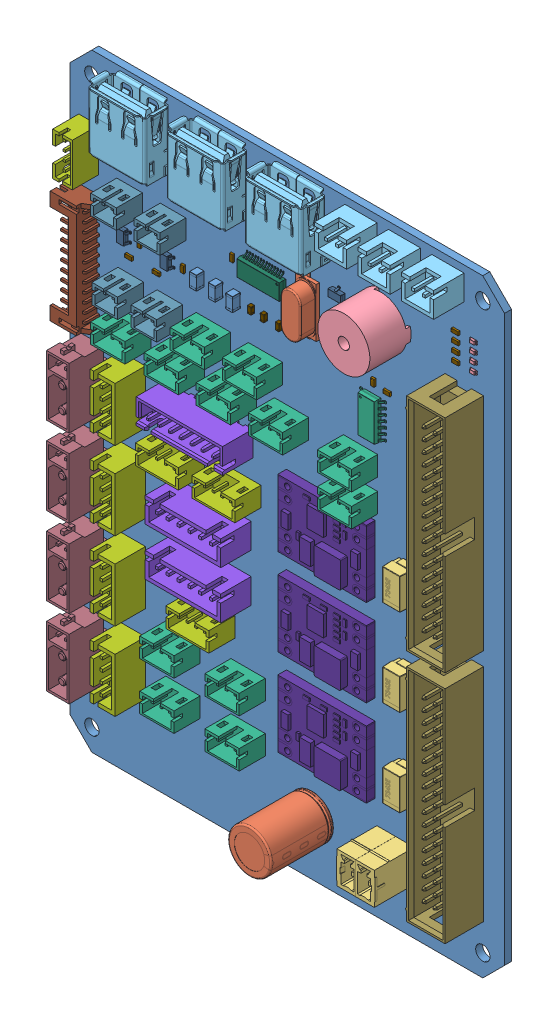
SolidWorks assembly Main Board, configuration 預設. Lengths in mm.
Overall size (100 140 20.2).
81 component instances, 26 part files, 0 mates.
Components (placement in the parent):
- BoardOutline_Main Board-1: BoardOutline_Main Board [預設] at origin size (100 140 1.6)
- XTAL_ECS-120-32-5P-TR_ECS-120-32-5P-TR_1-1: XTAL_ECS-120-32-5P-TR_ECS-120-32-5P-TR_1 [預設] at (267.025 238.5 1.6) x (0 1 0) z (0 0 1) size (13.2 4.8 4.31)
- FCI_06-381-2PIN_(180)_2_Pin_1-1: FCI_06-381-2PIN_(180)_2_Pin_1 [預設] at (287.025 139.5 1.6) size (8.81 7.6 12.7)
- LED_0603_1608_BLUE_LED_1-1: LED_0603_1608_BLUE_LED_1 [預設] at (305 250.5 1.6) size (1.6 0.8 0.53)
- LED_0603_1608_BLUE_LED_1-2: LED_0603_1608_BLUE_LED_1 [預設] at (305.025 248.5 1.6) size (1.6 0.8 0.53)
- LED_0603_1608_BLUE_LED_1-3: LED_0603_1608_BLUE_LED_1 [預設] at (305.025 246.5 1.6) size (1.6 0.8 0.53)
- LED_0603_1608_BLUE_LED_1-4: LED_0603_1608_BLUE_LED_1 [預設] at (305.025 244.5 1.6) size (1.6 0.8 0.53)
- OST_USB-A1HSW6_USB-A1HSW6_1-1: OST_USB-A1HSW6_USB-A1HSW6_1 [預設] at (229 256.5 1.6) x (-1 0 0) z (0 0 1) size (15.8 14.1 10.8)
- OST_USB-A1HSW6_USB-A1HSW6_1-2: OST_USB-A1HSW6_USB-A1HSW6_1 [預設] at (247 256.5 1.6) x (-1 0 0) z (0 0 1) size (15.8 14.1 10.8)
- OST_USB-A1HSW6_USB-A1HSW6_1-3: OST_USB-A1HSW6_USB-A1HSW6_1 [預設] at (265 256.5 1.6) x (-1 0 0) z (0 0 1) size (15.8 14.1 10.8)
- JST_B3B-PH-K_3_Pin_1-1: JST_B3B-PH-K_3_Pin_1 [預設] at (251 214.5 1.6) size (7.9 4.5 9.4)
- JST_B3B-PH-K_3_Pin_1-2: JST_B3B-PH-K_3_Pin_1 [預設] at (263 214.5 1.6) size (7.9 4.5 9.4)
- JST_B3B-PH-K_3_Pin_1-3: JST_B3B-PH-K_3_Pin_1 [預設] at (278.875 207.7 1.6) size (7.9 4.5 9.4)
- JST_B3B-PH-K_3_Pin_1-4: JST_B3B-PH-K_3_Pin_1 [預設] at (278.875 215.075 1.6) size (7.9 4.5 9.4)
- JST_B3B-PH-K_3_Pin_1-5: JST_B3B-PH-K_3_Pin_1 [預設] at (253 146.5 1.6) size (7.9 4.5 9.4)
- JST_B3B-PH-K_3_Pin_1-6: JST_B3B-PH-K_3_Pin_1 [預設] at (238 157.5 1.6) size (7.9 4.5 9.4)
- JST_B3B-PH-K_3_Pin_1-7: JST_B3B-PH-K_3_Pin_1 [預設] at (253 157.5 1.6) size (7.9 4.5 9.4)
- JST_B3B-PH-K_3_Pin_1-8: JST_B3B-PH-K_3_Pin_1 [預設] at (245 222.5 1.6) size (7.9 4.5 9.4)
- JST_B3B-PH-K_3_Pin_1-9: JST_B3B-PH-K_3_Pin_1 [預設] at (257 222.5 1.6) size (7.9 4.5 9.4)
- JST_B3B-PH-K_3_Pin_1-10: JST_B3B-PH-K_3_Pin_1 [預設] at (238 146.5 1.6) size (7.9 4.5 9.4)
- JST_B3B-PH-K_3_Pin_1-11: JST_B3B-PH-K_3_Pin_1 [預設] at (226.6878 214.4734 1.6) size (7.9 4.5 9.4)
- JST_B3B-PH-K_3_Pin_1-12: JST_B3B-PH-K_3_Pin_1 [預設] at (239 214.5 1.6) size (7.9 4.5 9.4)
- JST_B4B-PH-K_4_Pin_1-1: JST_B4B-PH-K_4_Pin_1 [預設] at (238 195.5 1.6) size (9.9 4.5 9.4)
- JST_B4B-PH-K_4_Pin_1-2: JST_B4B-PH-K_4_Pin_1 [預設] at (251 195.5 1.6) size (9.9 4.5 9.4)
- JST_B4B-PH-K_4_Pin_1-3: JST_B4B-PH-K_4_Pin_1 [預設] at (245 166.5 1.6) size (9.9 4.5 9.4)
- JST_B4B-PH-K_4_Pin_1-4: JST_B4B-PH-K_4_Pin_1 [預設] at (215.725 245.3 1.6) x (0 1 0) z (0 0 1) size (9.9 4.5 9.4)
- JST_XH_B6B-XH-A_6_Pin_1-1: JST_XH_B6B-XH-A_6_Pin_1 [預設] at (245 175.5 1.6) size (17.4 5.75 10.4)
- JST_XH_B6B-XH-A_6_Pin_1-2: JST_XH_B6B-XH-A_6_Pin_1 [預設] at (245 186.5 1.6) size (17.4 5.75 10.4)
- RES_0603_1608_RF_Resistor_1-1: RES_0603_1608_RF_Resistor_1 [預設] at (301 250.5 1.6) x (-1 0 0) z (0 0 1) size (1.6 0.8 0.45)
- RES_0603_1608_RF_Resistor_1-2: RES_0603_1608_RF_Resistor_1 [預設] at (249.525 239.5 1.6) x (0 1 0) z (0 0 1) size (1.6 0.8 0.45)
- RES_0603_1608_RF_Resistor_1-3: RES_0603_1608_RF_Resistor_1 [預設] at (225.85 227.775 1.6) size (1.6 0.8 0.45)
- RES_0603_1608_RF_Resistor_1-4: RES_0603_1608_RF_Resistor_1 [預設] at (232.15 227.8 1.6) size (1.6 0.8 0.45)
- RES_0603_1608_RF_Resistor_1-5: RES_0603_1608_RF_Resistor_1 [預設] at (233.725 235.15 1.6) x (0 1 0) z (0 0 1) size (1.6 0.8 0.45)
- RES_0603_1608_RF_Resistor_1-6: RES_0603_1608_RF_Resistor_1 [預設] at (223.725 235.15 1.6) x (0 1 0) z (0 0 1) size (1.6 0.8 0.45)
- RES_0603_1608_RF_Resistor_1-7: RES_0603_1608_RF_Resistor_1 [預設] at (238.225 231.65 1.6) x (0 -1 0) z (0 0 1) size (1.6 0.8 0.45)
- RES_0603_1608_RF_Resistor_1-8: RES_0603_1608_RF_Resistor_1 [預設] at (228.225 231.65 1.6) x (0 -1 0) z (0 0 1) size (1.6 0.8 0.45)
- RES_0603_1608_RF_Resistor_1-9: RES_0603_1608_RF_Resistor_1 [預設] at (285.25 230.45 1.6) size (1.6 0.8 0.45)
- RES_0603_1608_RF_Resistor_1-10: RES_0603_1608_RF_Resistor_1 [預設] at (273.85 240.125 1.6) x (0 1 0) z (0 0 1) size (1.6 0.8 0.45)
- RES_0603_1608_RF_Resistor_1-11: RES_0603_1608_RF_Resistor_1 [預設] at (282.025 230.95 1.6) x (0 1 0) z (0 0 1) size (1.6 0.8 0.45)
- RES_0603_1608_RF_Resistor_1-12: RES_0603_1608_RF_Resistor_1 [預設] at (301.025 244.5 1.6) x (-1 0 0) z (0 0 1) size (1.6 0.8 0.45)
- RES_0603_1608_RF_Resistor_1-13: RES_0603_1608_RF_Resistor_1 [預設] at (301.025 248.5 1.6) x (-1 0 0) z (0 0 1) size (1.6 0.8 0.45)
- RES_0603_1608_RF_Resistor_1-14: RES_0603_1608_RF_Resistor_1 [預設] at (301.025 246.5 1.6) x (-1 0 0) z (0 0 1) size (1.6 0.8 0.45)
- SOT-23-3_SINGLE_N-MOSFET_1-1: SOT-23-3_SINGLE_N-MOSFET_1 [預設] at (234.725 231.65 1.6) x (0 1 0) z (0 0 1) size (3.01 2.84 1.18)
- SOT-23-3_SINGLE_N-MOSFET_1-2: SOT-23-3_SINGLE_N-MOSFET_1 [預設] at (224.725 231.65 1.6) x (0 1 0) z (0 0 1) size (3.01 2.84 1.18)
- SOT-23-3_SINGLE_N-MOSFET_1-3: SOT-23-3_SINGLE_N-MOSFET_1 [預設] at (274.025 244.5 1.6) size (3.01 2.84 1.18)
- JST_S12B-PH-K_12_Pin_1-1: JST_S12B-PH-K_12_Pin_1 [預設] at (218.5 223.45 1.6) x (0 1 0) z (0 0 1) size (25.9 7.6 8.2)
- MYRIO_MXP_PORT_VERTICAL_2x17_Pin_1-1: MYRIO_MXP_PORT_VERTICAL_2x17_Pin_1 [預設] at (303.025 161.5 1.6) x (0 -1 0) z (0 0 1) size (50.84 9.1 12.1)
- MYRIO_MXP_PORT_VERTICAL_2x17_Pin_1-2: MYRIO_MXP_PORT_VERTICAL_2x17_Pin_1 [預設] at (303.025 215.5 1.6) x (0 -1 0) z (0 0 1) size (50.84 9.1 12.1)
- XT30PB(2+2)_XT30(2+2)_1-1: XT30PB(2+2)_XT30(2+2)_1 [預設] at (218 163.5 1.6) x (0 1 0) z (0 0 1) size (15.5 5.2 11.3)
- XT30PB(2+2)_XT30(2+2)_1-2: XT30PB(2+2)_XT30(2+2)_1 [預設] at (218 145.5 1.6) x (0 1 0) z (0 0 1) size (15.5 5.2 11.3)
- XT30PB(2+2)_XT30(2+2)_1-3: XT30PB(2+2)_XT30(2+2)_1 [預設] at (218 199.5 1.6) x (0 1 0) z (0 0 1) size (15.5 5.2 11.3)
- XT30PB(2+2)_XT30(2+2)_1-4: XT30PB(2+2)_XT30(2+2)_1 [預設] at (218 181.5 1.6) x (0 1 0) z (0 0 1) size (15.5 5.2 11.3)
- JST_B2B-PH-K_2_Pin_1-1: JST_B2B-PH-K_2_Pin_1 [預設] at (235.725 240.15 1.6) size (5.9 4.5 9.4)
- JST_B2B-PH-K_2_Pin_1-2: JST_B2B-PH-K_2_Pin_1 [預設] at (225.725 240.15 1.6) size (5.9 4.5 9.4)
- JST_B2B-PH-K_2_Pin_1-3: JST_B2B-PH-K_2_Pin_1 [預設] at (235 222.5 1.6) size (5.9 4.5 9.4)
- JST_B2B-PH-K_2_Pin_1-4: JST_B2B-PH-K_2_Pin_1 [預設] at (226 222.5 1.6) size (5.9 4.5 9.4)
- SOP64P600X175-28N_FE1.1S_1-1: SOP64P600X175-28N_FE1.1S_1 [預設] at (257.025 239.5 1.6) x (0 -1 0) z (0 0 1) size (6 9.9 1.75)
- SOT95P280X145-5N_SN74AHC1G04DBVR_1-1: SOT95P280X145-5N_SN74AHC1G04DBVR_1 [預設] at (276.75 232.975 1.6) size (2.43 2.79 1.09)
- MP1584EN_DC-DC_Component_1_1-1: MP1584EN_DC-DC_Component_1_1 [預設] at (272.025 195.5 1.6) x (-1 0 0) z (0 0 1) size (20.4 15.4 3.6)
- MP1584EN_DC-DC_Component_1_1-2: MP1584EN_DC-DC_Component_1_1 [預設] at (272.025 175.5 1.6) x (-1 0 0) z (0 0 1) size (20.4 15.4 3.6)
- MP1584EN_DC-DC_Component_1_1-3: MP1584EN_DC-DC_Component_1_1 [預設] at (272.025 155.5 1.6) x (-1 0 0) z (0 0 1) size (20.4 15.4 3.6)
- CAP_0603_1608_RF_Capacitor_1-1: CAP_0603_1608_RF_Capacitor_1 [預設] at (260.5 231.45 1.6) x (0 1 0) z (0 0 1) size (1.6 0.82 0.82)
- CAP_0603_1608_RF_Capacitor_1-2: CAP_0603_1608_RF_Capacitor_1 [預設] at (254.075 231.55 1.6) x (0 1 0) z (0 0 1) size (1.6 0.82 0.82)
- CAP_0603_1608_RF_Capacitor_1-3: CAP_0603_1608_RF_Capacitor_1 [預設] at (257.025 231.5 1.6) x (0 1 0) z (0 0 1) size (1.6 0.82 0.82)
- CAP_1206_3216_-_1.8MM_Capacitor_1-1: CAP_1206_3216_-_1.8MM_Capacitor_1 [預設] at (242.1 231.8 1.6) x (0 -1 0) z (0 0 1) size (3.2 1.6 1.8)
- CAP_1206_3216_-_1.8MM_Capacitor_1-2: CAP_1206_3216_-_1.8MM_Capacitor_1 [預設] at (250.425 231.675 1.6) x (0 -1 0) z (0 0 1) size (3.2 1.6 1.8)
- CAP_1206_3216_-_1.8MM_Capacitor_1-3: CAP_1206_3216_-_1.8MM_Capacitor_1 [預設] at (246.4 231.75 1.6) x (0 -1 0) z (0 0 1) size (3.2 1.6 1.8)
- CAP_AL_TH_D10_L5_H14.5_Polarised_Capacitor_1-1: CAP_AL_TH_D10_L5_H14.5_Polarised_Capacitor_1 [預設] at (268.025 137.5 1.6) size (10 10 17.7)
- CAP_POL_2917_7343_Polarised_Capacitor_1-1: CAP_POL_2917_7343_Polarised_Capacitor_1 [預設] at (290.025 175.5 1.6) x (0 1 0) z (0 0 1) size (7.3 4.3 4.1)
- CAP_POL_2917_7343_Polarised_Capacitor_1-2: CAP_POL_2917_7343_Polarised_Capacitor_1 [預設] at (290.025 195.5 1.6) x (0 1 0) z (0 0 1) size (7.3 4.3 4.1)
- CAP_POL_2917_7343_Polarised_Capacitor_1-3: CAP_POL_2917_7343_Polarised_Capacitor_1 [預設] at (290.025 155.5 1.6) x (0 1 0) z (0 0 1) size (7.3 4.3 4.1)
- BZ_ZK-1205S_Buzzer_1-1: BZ_ZK-1205S_Buzzer_1 [預設] at (284.525 244.5 1.6) size (12 12 15)
- JST_XH_B2B-XH-A_2_Pin_1-1: JST_XH_B2B-XH-A_2_Pin_1 [預設] at (299 260.5 1.6) size (7.4 5.75 10.4)
- JST_XH_B2B-XH-A_2_Pin_1-2: JST_XH_B2B-XH-A_2_Pin_1 [預設] at (289 260.5 1.6) size (7.4 5.75 10.4)
- JST_XH_B2B-XH-A_2_Pin_1-3: JST_XH_B2B-XH-A_2_Pin_1 [預設] at (279 260.5 1.6) size (7.4 5.75 10.4)
- SOIC127P600X175-14N_SN74HC126DG4_1-1: SOIC127P600X175-14N_SN74HC126DG4_1 [預設] at (281.9 224.35 1.6) size (6 8.65 1.75)
- JST_XH_B4B-XH-A_4_Pin_1-1: JST_XH_B4B-XH-A_4_Pin_1 [預設] at (226 147.5 1.6) x (0 1 0) z (0 0 1) size (12.4 5.75 10.4)
- JST_XH_B4B-XH-A_4_Pin_1-2: JST_XH_B4B-XH-A_4_Pin_1 [預設] at (226 165.5 1.6) x (0 1 0) z (0 0 1) size (12.4 5.75 10.4)
- JST_XH_B4B-XH-A_4_Pin_1-3: JST_XH_B4B-XH-A_4_Pin_1 [預設] at (226 183.5 1.6) x (0 1 0) z (0 0 1) size (12.4 5.75 10.4)
- JST_XH_B4B-XH-A_4_Pin_1-4: JST_XH_B4B-XH-A_4_Pin_1 [預設] at (226 201.5 1.6) x (0 1 0) z (0 0 1) size (12.4 5.75 10.4)
- JST_XH_B7B-XH-90_7_Pin_1-1: JST_XH_B7B-XH-90_7_Pin_1 [預設] at (252 205.5 1.6) x (-1 0 0) z (0 0 1) size (19.9 5.75 10.4)
